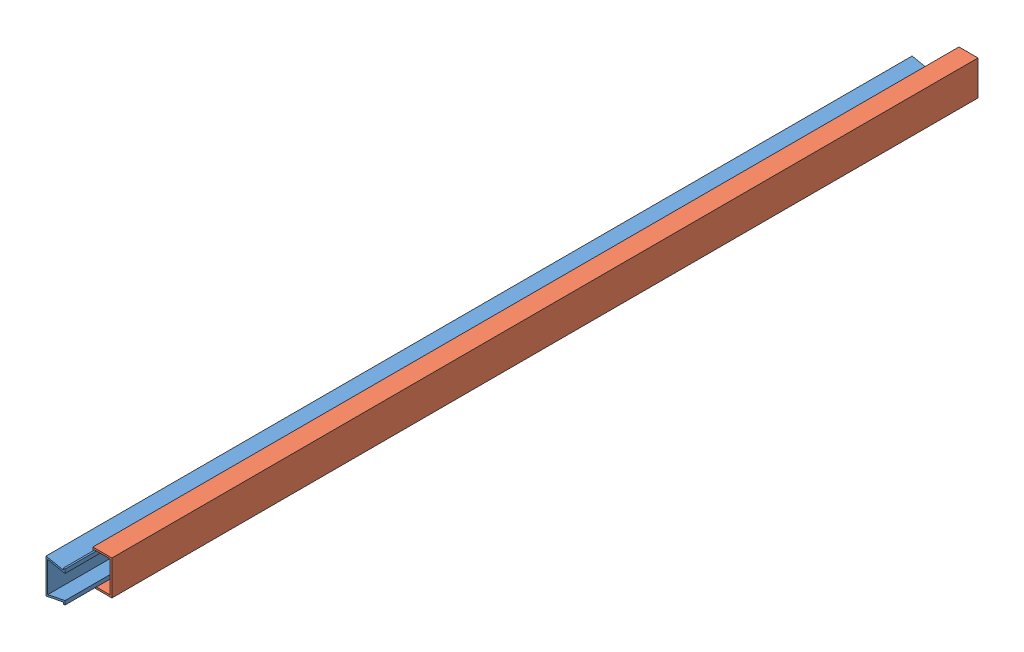
SolidWorks assembly Laufschienen, configuration Default. Lengths in mm.
Overall size (10 10 259.02).
2 component instances, 2 part files, 3 mates.
Components (placement in the parent):
- Laufschiene-1: Laufschiene [Default] at (60.7756 134.5373 79.8501) size (5.5 10 250)
- Laufschiene-Neg-1: Laufschiene-Neg [Default] at (70.7756 134.5373 70.8278) size (5.5 10 250)
Mates (geometry in assembly coordinates):
- Deckungsgleich1: coincident anti-aligned: plane of Laufschiene-1 through (65.7756 138.5373 329.8501) normal (-1 0 0); plane of Laufschiene-Neg-1 through (65.7756 139.0373 320.8278) normal (1 0 0)
- Deckungsgleich2: coincident anti-aligned: plane of Laufschiene-1 through (65.7756 139.0373 329.8501) normal (0 1 0); plane of Laufschiene-Neg-1 through (70.2756 139.0373 320.8278) normal (0 -1 0)
- LimitAbstand1: limit distance = 9.0223 mm aligned: plane of Laufschiene-1 through (60.7756 134.5373 329.8501) normal (0 0 1); plane of Laufschiene-Neg-1 through (70.7756 134.5373 320.8278) normal (0 0 1)
